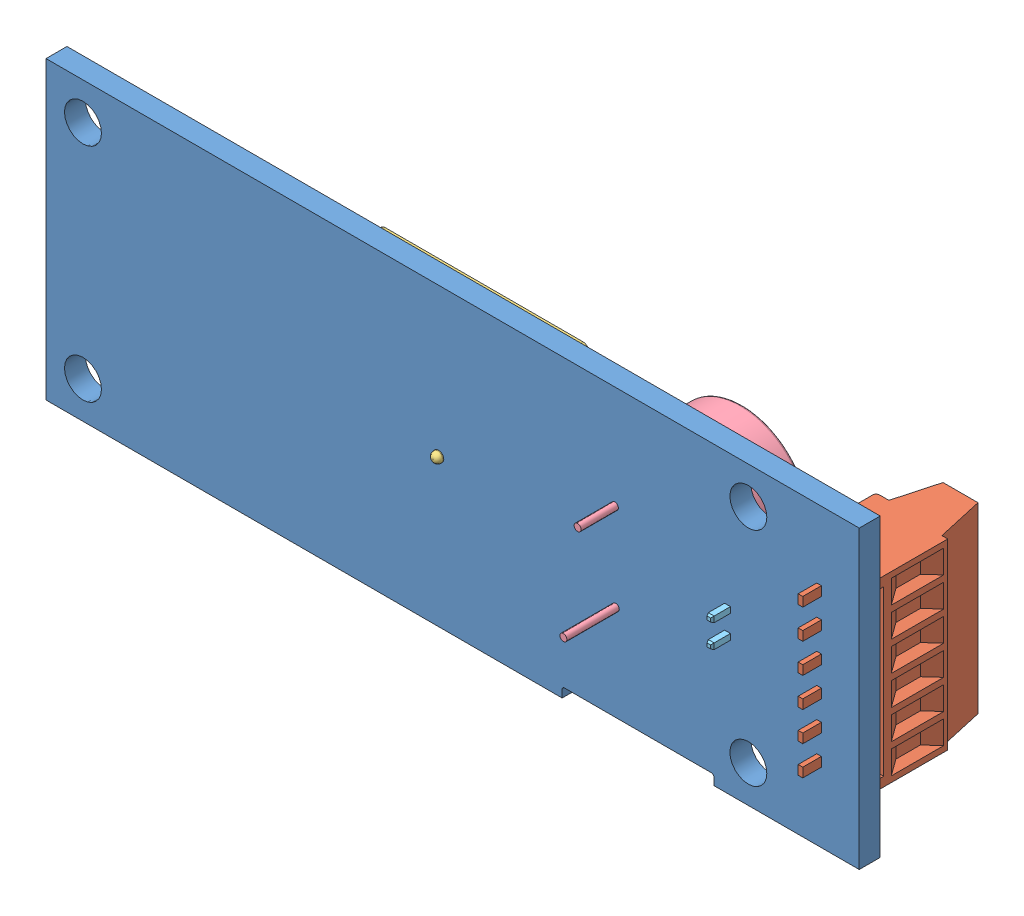
SolidWorks assembly Altus Telemetrum, configuration Varsayılan. Lengths in mm.
Overall size (210.19 163.33 16.3).
5 component instances, 5 part files, 12 mates.
Components (placement in the parent):
- Altus Telemetrum-1: Altus Telemetrum [Varsayılan] at (-4.428 -0.2509 69.85) size (210.19 163.33 1.8)
- Klemens 6lı-1: Klemens 6lı [Varsayılan] at (26.3858 -0.2109 59.85) x (0 -1 0) z (0 0 -1) size (15.7 6.5 13.4)
- Anten çip-1: Anten çip [Varsayılan] at (-6.3005 -0.2784 69.73) x (0 -1 0) z (1 0 0) size (18 6.9 18)
- Buzzer-1: Buzzer [Varsayılan] at (3.6118 -0.2033 39.45) x (-0.010052 0.999949 0) z (0.999949 0.010052 0) size (11.75 15.4 11.75)
- B2B-PH-K-S-1: B2B-PH-K-S [Varsayılan] at (16.8216 -3.1246 69.85) x (0 1 0) z (0 0 -1) size (5.9 4.5 9.4)
Mates (geometry in assembly coordinates):
- Çakışık2: coincident anti-aligned: plane of Altus Telemetrum-1 through (-4.428 -0.2509 69.85) normal (0 0 -1); plane of Anten çip-1 through (-6.3005 -0.2784 69.85) normal (0 0 1)
- Çakışık4: coincident: line of Altus Telemetrum-1 through (0.8995 8.7216 69.85) axis (0 -1 0); plane of Anten çip-1 through (0.8995 8.7216 69.53) normal (1 0 0)
- Çakışık5: coincident: line of Altus Telemetrum-1 through (-16.8513 8.7216 69.85) axis (1 0 0); plane of Anten çip-1 through (-17.1005 8.7216 69.53) normal (0 1 0)
- Çakışık6: coincident anti-aligned: plane of Altus Telemetrum-1 through (-4.428 -0.2509 69.85) normal (0 0 -1); plane of Buzzer-1 through (8.8866 -0.1503 69.85) normal (0 0 1)
- Eş Merkezli1: concentric anti-aligned: circle of Altus Telemetrum-1; cylinder of Buzzer-1 through (8.8866 -0.1503 60.75) axis (0 0 1) radius 5.875
- Çakışık8: coincident anti-aligned: plane of Altus Telemetrum-1 through (-4.428 -0.2509 69.85) normal (0 0 -1); plane of B2B-PH-K-S-1 through (19.0716 -0.1746 69.85) normal (0 0 1)
- Paralel5: parallel aligned: plane of Altus Telemetrum-1 through (17.1464 -12.1014 79.85) normal (0 -1 0); plane of B2B-PH-K-S-1 through (19.0716 -3.1246 66.85) normal (0 -1 0)
- Çakışık9: coincident: line of Altus Telemetrum-1 through (21.3216 2.7754 69.85) axis (0 -1 0); plane of B2B-PH-K-S-1 through (21.3216 -0.1746 66.85) normal (1 0 0)
- Çakışık10: coincident: line of Altus Telemetrum-1 through (16.8702 2.7754 69.85) axis (1 0 0); plane of B2B-PH-K-S-1 through (19.0716 2.7754 66.85) normal (0 1 0)
- Coincident1: coincident: line of Altus Telemetrum-1 through (29.6358 -8.0609 69.85) axis (-1 0 0); plane of Klemens 6lı-1 through (26.3858 -8.0609 59.85) normal (0 -1 0)
- Coincident2: coincident anti-aligned: plane of Altus Telemetrum-1 through (-4.428 -0.2509 69.85) normal (0 0 -1); plane of Klemens 6lı-1 through (23.1358 -8.0609 69.85) normal (0 0 1)
- Coincident3: coincident: line of Altus Telemetrum-1 through (29.6358 7.5591 69.85) axis (0 -1 0); plane of Klemens 6lı-1 through (29.6358 -8.0609 69.85) normal (1 0 0)
